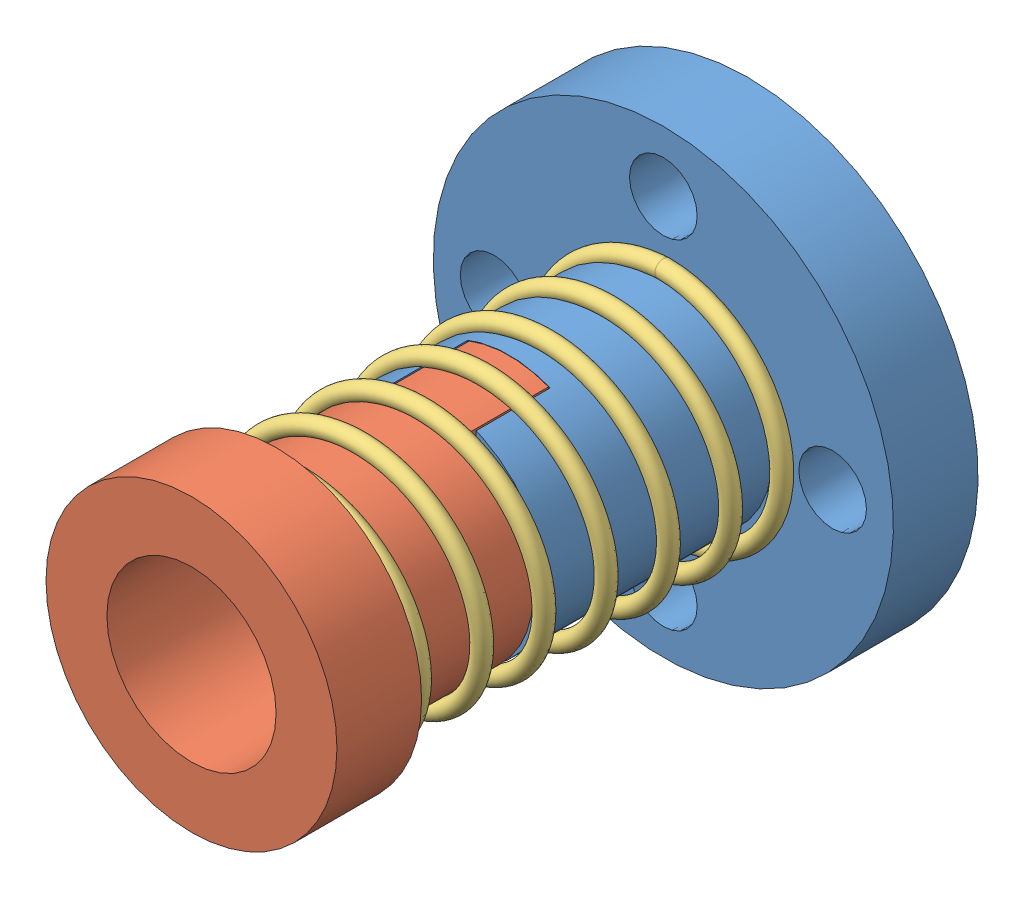
SolidWorks assembly TR08, configuration Predeterminado. Lengths in mm.
Overall size (21.75 21.75 26.3).
3 component instances, 3 part files, 4 mates.
Components (placement in the parent):
- nakretka tr08-1: nakretka tr08 [Predeterminado] at (20.7471 35.4278 19.4357) x (1 0 0) z (0 1 0) size (21.75 14.8 21.75)
- napinacz nakretki tr8-1: napinacz nakretki tr8 [Predeterminado] at (20.7471 35.4278 41.7357) x (-1 0 0) z (0 -1 0) size (13.75 15 13.75)
- sprezyna nakretka tr 8-1: sprezyna nakretka tr 8 [Predeterminado] at (21.1556 35.3914 19.8355) x (0.999661 0 0.026047) z (-0.026047 0 0.999661) size (12.35 12.39 19.87)
Mates (geometry in assembly coordinates):
- Tangente1: tangent: plane of nakretka tr08-1 through (20.7471 35.4278 19.4357) normal (0 0 1); face of sprezyna nakretka tr 8-1
- Coincidente1: coincident anti-aligned: plane of nakretka tr08-1 through (20.7471 30.2578 26.7357) normal (0 0 1); plane of napinacz nakretki tr8-1 through (20.7471 35.4278 26.7357) normal (0 0 -1)
- Concéntrica1: concentric anti-aligned: cylinder of nakretka tr08-1 through (20.7471 35.4278 19.4357) axis (0 0 1) radius 5.17; cylinder of napinacz nakretki tr8-1 through (20.7471 35.4278 37.7357) axis (0 0 -1) radius 5.15
- Tangente3: tangent: cylinder of nakretka tr08-1 through (20.7471 35.4278 19.4357) axis (0 0 1) radius 5.17; face of sprezyna nakretka tr 8-1
